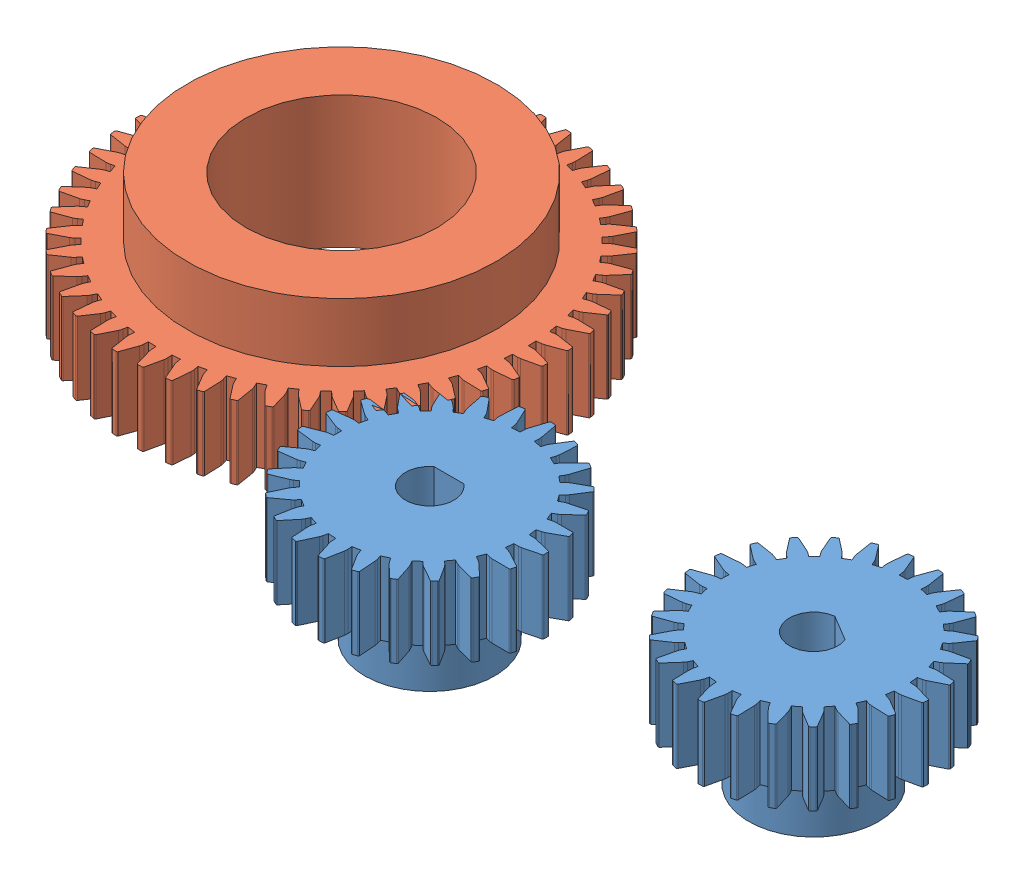
SolidWorks assembly Assem1, configuration Default. Lengths in mm.
Overall size (173.37 32.4 97.43).
3 component instances, 2 part files, 3 mates.
Components (placement in the parent):
- gear 1-1: gear 1 [Default] at (92.7386 0.0777 14.9051) x (0.858508 0 0.512801) z (-0.512801 0 0.858508) size (39.39 22.4 39.46)
- gear 1-2: gear 1 [Default] at (39.1944 0.0777 25.9759) size (39.39 22.4 39.46)
- gear big-1: gear big [Default] at (1.5606 0.0777 -4.0542) x (0.857876 0 -0.513856) z (0.513856 0 0.857876) size (70.97 22.4 71.06)
Mates (geometry in assembly coordinates):
- GearMate2: gear = 39.5 : 62.6 mm: cylinder of gear big-1 through (-4.8389 12.4777 -3.4246) axis (0 -1 0) radius 31.3; cylinder of gear 1-1 through (92.7555 12.4777 13.9963) axis (0 -1 0) radius 19.75
- Coincident2: coincident aligned: plane of gear 1-1 through (77.5747 12.4777 1.6777) normal (0 1 0); plane of gear big-1 through (1.5606 12.4777 -4.0542) normal (0 1 0)
- Coincident6: coincident aligned: plane of gear 1-2 through (19.3931 12.4777 22.3961) normal (0 1 0); plane of gear big-1 through (1.5606 12.4777 -4.0542) normal (0 1 0)
